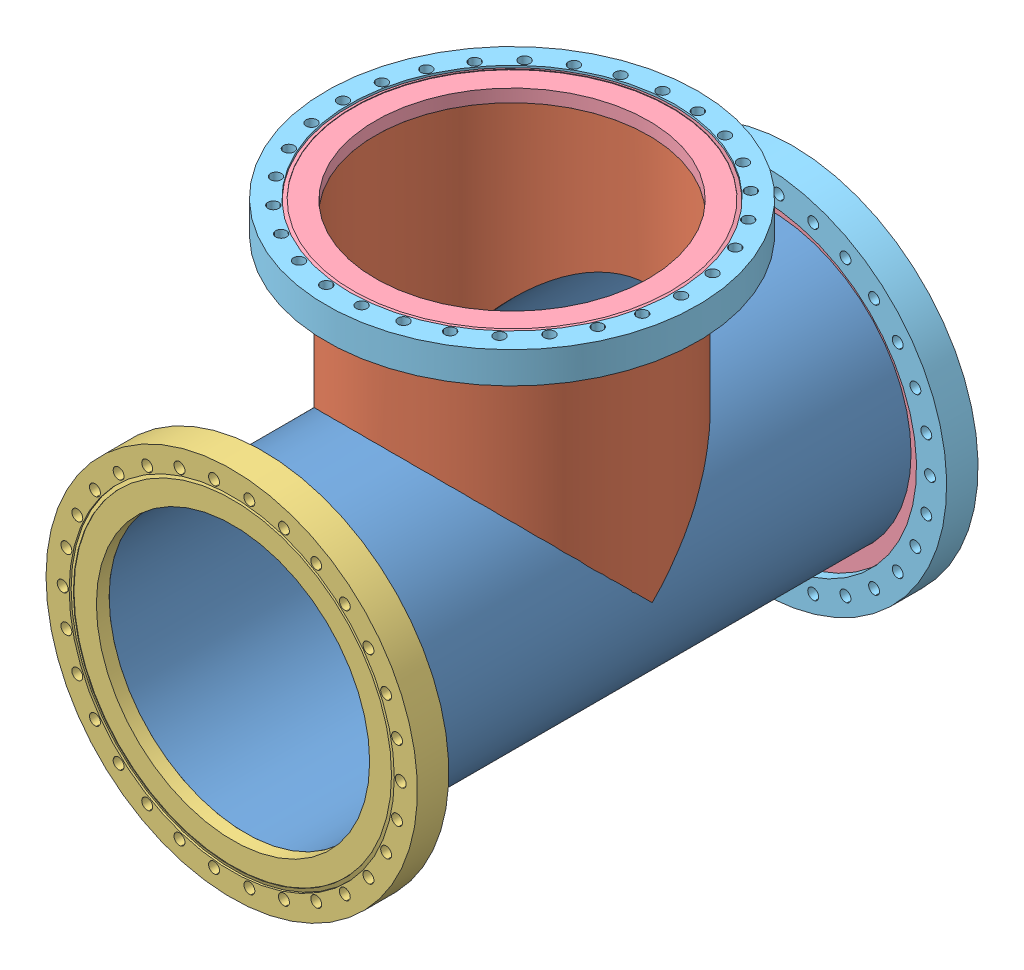
SolidWorks assembly 404010, configuration Default. Lengths in mm.
Overall size (336.55 422.28 508).
9 component instances, 5 part files, 0 mates.
Components (placement in the parent):
- 404010-001-1: 404010-001 [Default] at origin size (254 254 482.6)
- 404010-002-1: 404010-002 [Default] at (0 0 241.3) x (-1 0 0) z (0 1 0) size (254 254 254.74)
- 110035 (13.25 X 10.0 NR)-1: 110035 (13.25 X 10.0 NR) [Default] at (0 0 495.3) x (0 0 -1) z (0 1 0) size (28.45 336.55 336.55)
- 100035 (13.25 X 10.0 R)-1: 100035 (13.25 X 10.0 R) [Default] at (0 253.3396 241.3) x (0 -1 0) z (0 0 1) size (28.45 336.55 336.55)
  - 100035 (13.25 X 10.0 INS)-1: 100035 (13.25 X 10.0 INS) [Default] at origin size (19.02 294.64 294.64)
  - 100035 (13.25 X 10.0 REC)-1: 100035 (13.25 X 10.0 REC) [Default] at (-0.6604 0 0) size (28.45 336.55 336.55)
- 100035 (13.25 X 10.0 R)-2: 100035 (13.25 X 10.0 R) [Default] at (0 0 -12.0396) x (0 0 1) z (0 -1 0) size (28.45 336.55 336.55)
  - 100035 (13.25 X 10.0 INS)-1: 100035 (13.25 X 10.0 INS) [Default] at origin size (19.02 294.64 294.64)
  - 100035 (13.25 X 10.0 REC)-1: 100035 (13.25 X 10.0 REC) [Default] at (-0.6604 0 0) size (28.45 336.55 336.55)
